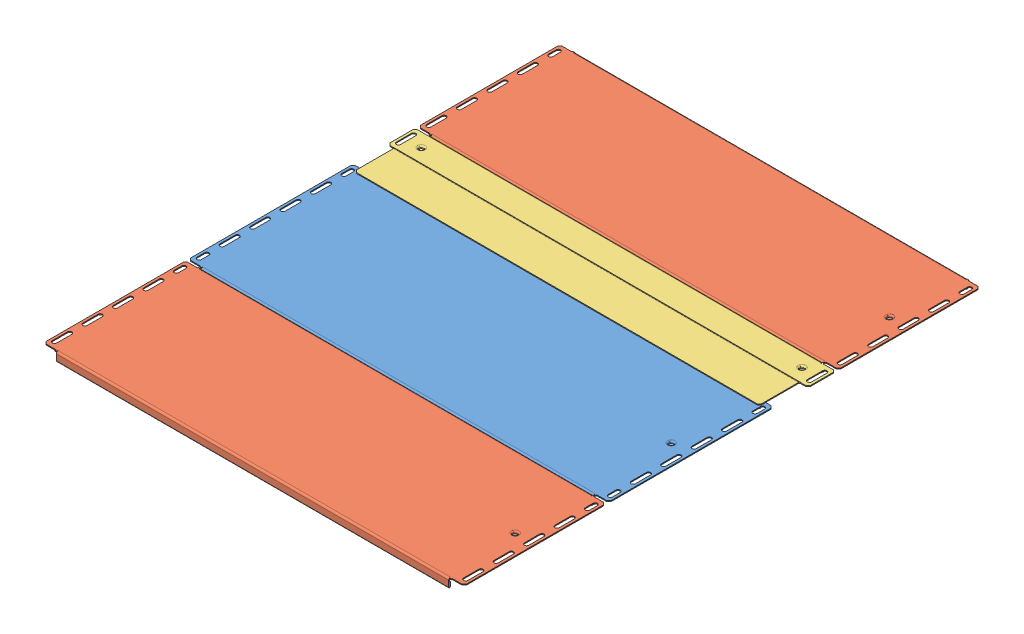
SolidWorks assembly 5301_344, configuration Default. Lengths in mm.
Overall size (690 16.1 852).
4 component instances, 3 part files, 0 mates.
Components (placement in the parent):
- 5301_344-bottom-slice2-1: 5301_344-bottom-slice2 [Default] at (0 0 188.5) x (-1 0 0) z (0 0 -1) size (690 14.5 275)
- 5301_344-bottom-slice1-1: 5301_344-bottom-slice1 [Default] at (0 0 426) x (-1 0 0) z (0 0 -1) size (690 14.5 237.5)
- 5301_344-bottom-slice3-1: 5301_344-bottom-slice3 [Default] at (0 0 -188.5) size (690 16.1 115)
- 5301_344-bottom-slice1-2: 5301_344-bottom-slice1 [Default] at (0 0 -188.5) x (-1 0 0) z (0 0 -1) size (690 14.5 237.5)
